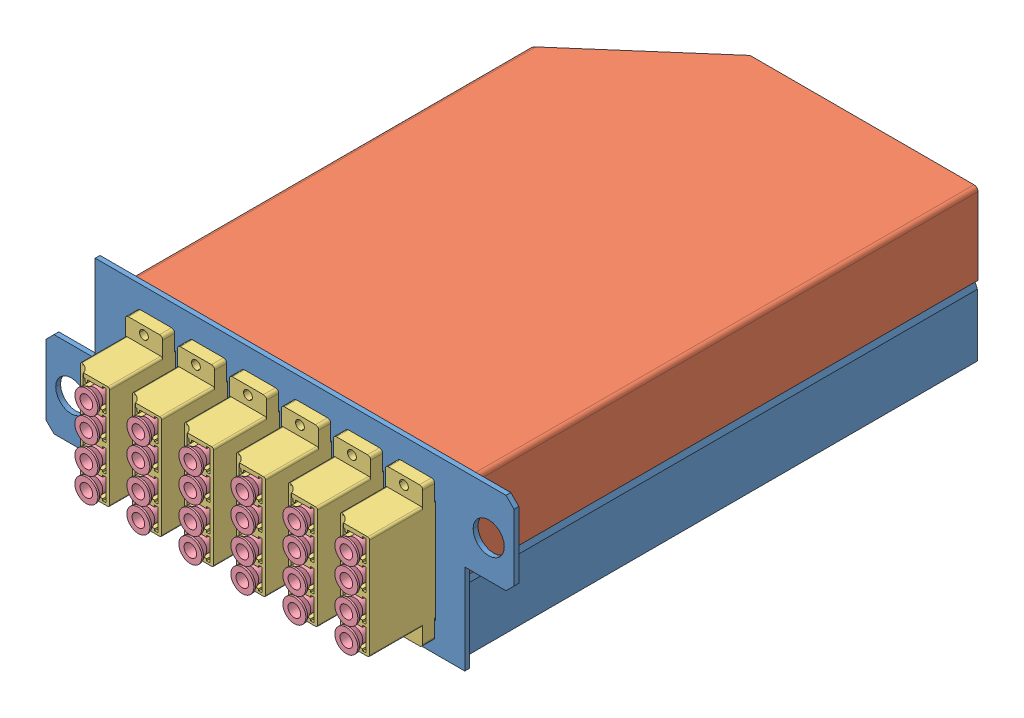
SolidWorks assembly Baugruppe5, configuration Standard. Lengths in mm.
Overall size (117 43.2 150.01).
62 component instances, 4 part files, 24 mates.
Components (placement in the parent):
- Cassette-1: Cassette [Standard] at (-81.5544 -7.2939 -1.2) size (117 43.2 131.2)
- Cassette Lid-1: Cassette Lid [Standard] at (-38.8731 -6.65 -32.039) size (86.6 20.2 130)
- LC-Adapter-1: LC-Adapter [Standard] at (-94.18 -5.525 16.25) x (0 1 0) z (0 0 1) size (34.9 10.05 34.47)
  - LC Adaptor-1: LC Adaptor [Standard] at (-28.4856 -9.35 -16.25) x (1 0 0) z (0 -1 0) size (34.9 25.75 9.35)
  - LC Adaptor Dust Cap-1: LC Adaptor Dust Cap [Standard] at (-27.05 -6.075 2.56) x (-0.837169 0.546944 0) z (-0.546944 -0.837169 0) size (5.75 16.66 5.75)
  - LC Adaptor Dust Cap-2: LC Adaptor Dust Cap [Standard] at (-20.85 -6.075 2.56) x (-0.837169 0.546944 0) z (-0.546944 -0.837169 0) size (5.75 16.66 5.75)
  - LC Adaptor Dust Cap-3: LC Adaptor Dust Cap [Standard] at (-14.05 -6.075 2.56) x (-0.837169 0.546944 0) z (-0.546944 -0.837169 0) size (5.75 16.66 5.75)
  - LC Adaptor Dust Cap-4: LC Adaptor Dust Cap [Standard] at (-7.85 -6.075 2.56) x (-0.837169 0.546944 0) z (-0.546944 -0.837169 0) size (5.75 16.66 5.75)
  - LC Adaptor Dust Cap-5: LC Adaptor Dust Cap [Standard] at (-27.05 -6.075 -31.91) x (0.972668 -0.232198 0) z (-0.232198 -0.972668 0) size (5.75 16.66 5.75)
  - LC Adaptor Dust Cap-6: LC Adaptor Dust Cap [Standard] at (-20.85 -6.075 -31.91) x (1 0 0) z (0 -1 0) size (5.75 16.66 5.75)
  - LC Adaptor Dust Cap-7: LC Adaptor Dust Cap [Standard] at (-14.05 -6.075 -31.91) x (0.97427 0.225385 0) z (0.225385 -0.97427 0) size (5.75 16.66 5.75)
  - LC Adaptor Dust Cap-8: LC Adaptor Dust Cap [Standard] at (-7.85 -6.075 -31.91) x (1 0 0) z (0 -1 0) size (5.75 16.66 5.75)
- LC-Adapter-2: LC-Adapter [Standard] at (-81.18 -5.525 16.25) x (0 1 0) z (0 0 1) size (34.9 10.05 34.47)
  - LC Adaptor-1: LC Adaptor [Standard] at (-28.4856 -9.35 -16.25) x (1 0 0) z (0 -1 0) size (34.9 25.75 9.35)
  - LC Adaptor Dust Cap-1: LC Adaptor Dust Cap [Standard] at (-27.05 -6.075 2.56) x (-0.837169 0.546944 0) z (-0.546944 -0.837169 0) size (5.75 16.66 5.75)
  - LC Adaptor Dust Cap-2: LC Adaptor Dust Cap [Standard] at (-20.85 -6.075 2.56) x (-0.837169 0.546944 0) z (-0.546944 -0.837169 0) size (5.75 16.66 5.75)
  - LC Adaptor Dust Cap-3: LC Adaptor Dust Cap [Standard] at (-14.05 -6.075 2.56) x (-0.837169 0.546944 0) z (-0.546944 -0.837169 0) size (5.75 16.66 5.75)
  - LC Adaptor Dust Cap-4: LC Adaptor Dust Cap [Standard] at (-7.85 -6.075 2.56) x (-0.837169 0.546944 0) z (-0.546944 -0.837169 0) size (5.75 16.66 5.75)
  - LC Adaptor Dust Cap-5: LC Adaptor Dust Cap [Standard] at (-27.05 -6.075 -31.91) x (0.972668 -0.232198 0) z (-0.232198 -0.972668 0) size (5.75 16.66 5.75)
  - LC Adaptor Dust Cap-6: LC Adaptor Dust Cap [Standard] at (-20.85 -6.075 -31.91) x (1 0 0) z (0 -1 0) size (5.75 16.66 5.75)
  - LC Adaptor Dust Cap-7: LC Adaptor Dust Cap [Standard] at (-14.05 -6.075 -31.91) x (0.97427 0.225385 0) z (0.225385 -0.97427 0) size (5.75 16.66 5.75)
  - LC Adaptor Dust Cap-8: LC Adaptor Dust Cap [Standard] at (-7.85 -6.075 -31.91) x (1 0 0) z (0 -1 0) size (5.75 16.66 5.75)
- LC-Adapter-3: LC-Adapter [Standard] at (-68.18 -5.525 16.25) x (0 1 0) z (0 0 1) size (34.9 10.05 34.47)
  - LC Adaptor-1: LC Adaptor [Standard] at (-28.4856 -9.35 -16.25) x (1 0 0) z (0 -1 0) size (34.9 25.75 9.35)
  - LC Adaptor Dust Cap-1: LC Adaptor Dust Cap [Standard] at (-27.05 -6.075 2.56) x (-0.837169 0.546944 0) z (-0.546944 -0.837169 0) size (5.75 16.66 5.75)
  - LC Adaptor Dust Cap-2: LC Adaptor Dust Cap [Standard] at (-20.85 -6.075 2.56) x (-0.837169 0.546944 0) z (-0.546944 -0.837169 0) size (5.75 16.66 5.75)
  - LC Adaptor Dust Cap-3: LC Adaptor Dust Cap [Standard] at (-14.05 -6.075 2.56) x (-0.837169 0.546944 0) z (-0.546944 -0.837169 0) size (5.75 16.66 5.75)
  - LC Adaptor Dust Cap-4: LC Adaptor Dust Cap [Standard] at (-7.85 -6.075 2.56) x (-0.837169 0.546944 0) z (-0.546944 -0.837169 0) size (5.75 16.66 5.75)
  - LC Adaptor Dust Cap-5: LC Adaptor Dust Cap [Standard] at (-27.05 -6.075 -31.91) x (0.972668 -0.232198 0) z (-0.232198 -0.972668 0) size (5.75 16.66 5.75)
  - LC Adaptor Dust Cap-6: LC Adaptor Dust Cap [Standard] at (-20.85 -6.075 -31.91) x (1 0 0) z (0 -1 0) size (5.75 16.66 5.75)
  - LC Adaptor Dust Cap-7: LC Adaptor Dust Cap [Standard] at (-14.05 -6.075 -31.91) x (0.97427 0.225385 0) z (0.225385 -0.97427 0) size (5.75 16.66 5.75)
  - LC Adaptor Dust Cap-8: LC Adaptor Dust Cap [Standard] at (-7.85 -6.075 -31.91) x (1 0 0) z (0 -1 0) size (5.75 16.66 5.75)
- LC-Adapter-4: LC-Adapter [Standard] at (-55.18 -5.525 16.25) x (0 1 0) z (0 0 1) size (34.9 10.05 34.47)
  - LC Adaptor-1: LC Adaptor [Standard] at (-28.4856 -9.35 -16.25) x (1 0 0) z (0 -1 0) size (34.9 25.75 9.35)
  - LC Adaptor Dust Cap-1: LC Adaptor Dust Cap [Standard] at (-27.05 -6.075 2.56) x (-0.837169 0.546944 0) z (-0.546944 -0.837169 0) size (5.75 16.66 5.75)
  - LC Adaptor Dust Cap-2: LC Adaptor Dust Cap [Standard] at (-20.85 -6.075 2.56) x (-0.837169 0.546944 0) z (-0.546944 -0.837169 0) size (5.75 16.66 5.75)
  - LC Adaptor Dust Cap-3: LC Adaptor Dust Cap [Standard] at (-14.05 -6.075 2.56) x (-0.837169 0.546944 0) z (-0.546944 -0.837169 0) size (5.75 16.66 5.75)
  - LC Adaptor Dust Cap-4: LC Adaptor Dust Cap [Standard] at (-7.85 -6.075 2.56) x (-0.837169 0.546944 0) z (-0.546944 -0.837169 0) size (5.75 16.66 5.75)
  - LC Adaptor Dust Cap-5: LC Adaptor Dust Cap [Standard] at (-27.05 -6.075 -31.91) x (0.972668 -0.232198 0) z (-0.232198 -0.972668 0) size (5.75 16.66 5.75)
  - LC Adaptor Dust Cap-6: LC Adaptor Dust Cap [Standard] at (-20.85 -6.075 -31.91) x (1 0 0) z (0 -1 0) size (5.75 16.66 5.75)
  - LC Adaptor Dust Cap-7: LC Adaptor Dust Cap [Standard] at (-14.05 -6.075 -31.91) x (0.97427 0.225385 0) z (0.225385 -0.97427 0) size (5.75 16.66 5.75)
  - LC Adaptor Dust Cap-8: LC Adaptor Dust Cap [Standard] at (-7.85 -6.075 -31.91) x (1 0 0) z (0 -1 0) size (5.75 16.66 5.75)
- LC-Adapter-5: LC-Adapter [Standard] at (-42.18 -5.525 16.25) x (0 1 0) z (0 0 1) size (34.9 10.05 34.47)
  - LC Adaptor-1: LC Adaptor [Standard] at (-28.4856 -9.35 -16.25) x (1 0 0) z (0 -1 0) size (34.9 25.75 9.35)
  - LC Adaptor Dust Cap-1: LC Adaptor Dust Cap [Standard] at (-27.05 -6.075 2.56) x (-0.837169 0.546944 0) z (-0.546944 -0.837169 0) size (5.75 16.66 5.75)
  - LC Adaptor Dust Cap-2: LC Adaptor Dust Cap [Standard] at (-20.85 -6.075 2.56) x (-0.837169 0.546944 0) z (-0.546944 -0.837169 0) size (5.75 16.66 5.75)
  - LC Adaptor Dust Cap-3: LC Adaptor Dust Cap [Standard] at (-14.05 -6.075 2.56) x (-0.837169 0.546944 0) z (-0.546944 -0.837169 0) size (5.75 16.66 5.75)
  - LC Adaptor Dust Cap-4: LC Adaptor Dust Cap [Standard] at (-7.85 -6.075 2.56) x (-0.837169 0.546944 0) z (-0.546944 -0.837169 0) size (5.75 16.66 5.75)
  - LC Adaptor Dust Cap-5: LC Adaptor Dust Cap [Standard] at (-27.05 -6.075 -31.91) x (0.972668 -0.232198 0) z (-0.232198 -0.972668 0) size (5.75 16.66 5.75)
  - LC Adaptor Dust Cap-6: LC Adaptor Dust Cap [Standard] at (-20.85 -6.075 -31.91) x (1 0 0) z (0 -1 0) size (5.75 16.66 5.75)
  - LC Adaptor Dust Cap-7: LC Adaptor Dust Cap [Standard] at (-14.05 -6.075 -31.91) x (0.97427 0.225385 0) z (0.225385 -0.97427 0) size (5.75 16.66 5.75)
  - LC Adaptor Dust Cap-8: LC Adaptor Dust Cap [Standard] at (-7.85 -6.075 -31.91) x (1 0 0) z (0 -1 0) size (5.75 16.66 5.75)
- LC-Adapter-6: LC-Adapter [Standard] at (-29.18 -5.525 16.25) x (0 1 0) z (0 0 1) size (34.9 10.05 34.47)
  - LC Adaptor-1: LC Adaptor [Standard] at (-28.4856 -9.35 -16.25) x (1 0 0) z (0 -1 0) size (34.9 25.75 9.35)
  - LC Adaptor Dust Cap-1: LC Adaptor Dust Cap [Standard] at (-27.05 -6.075 2.56) x (-0.837169 0.546944 0) z (-0.546944 -0.837169 0) size (5.75 16.66 5.75)
  - LC Adaptor Dust Cap-2: LC Adaptor Dust Cap [Standard] at (-20.85 -6.075 2.56) x (-0.837169 0.546944 0) z (-0.546944 -0.837169 0) size (5.75 16.66 5.75)
  - LC Adaptor Dust Cap-3: LC Adaptor Dust Cap [Standard] at (-14.05 -6.075 2.56) x (-0.837169 0.546944 0) z (-0.546944 -0.837169 0) size (5.75 16.66 5.75)
  - LC Adaptor Dust Cap-4: LC Adaptor Dust Cap [Standard] at (-7.85 -6.075 2.56) x (-0.837169 0.546944 0) z (-0.546944 -0.837169 0) size (5.75 16.66 5.75)
  - LC Adaptor Dust Cap-5: LC Adaptor Dust Cap [Standard] at (-27.05 -6.075 -31.91) x (0.972668 -0.232198 0) z (-0.232198 -0.972668 0) size (5.75 16.66 5.75)
  - LC Adaptor Dust Cap-6: LC Adaptor Dust Cap [Standard] at (-20.85 -6.075 -31.91) x (1 0 0) z (0 -1 0) size (5.75 16.66 5.75)
  - LC Adaptor Dust Cap-7: LC Adaptor Dust Cap [Standard] at (-14.05 -6.075 -31.91) x (0.97427 0.225385 0) z (0.225385 -0.97427 0) size (5.75 16.66 5.75)
  - LC Adaptor Dust Cap-8: LC Adaptor Dust Cap [Standard] at (-7.85 -6.075 -31.91) x (1 0 0) z (0 -1 0) size (5.75 16.66 5.75)
Mates (geometry in assembly coordinates):
- Deckungsgleich1: coincident: plane of Cassette-1 through (-81.5544 -7.2939 0) normal (0 0 1); plane of assembly
- Deckungsgleich2: coincident: plane of Cassette-1 through (-104.7 0 0) normal (0 1 0); plane of assembly
- Deckungsgleich3: coincident aligned: plane of Cassette-1 through (0 0 0) normal (1 0 0); plane of assembly
- Deckungsgleich4: coincident: plane of Cassette-1 through (-81.5544 -6.65 -1.2) normal (0 1 0); plane of Cassette Lid-1 through (-38.8731 -6.65 -32.039) normal (0 -1 0)
- Deckungsgleich5: coincident: plane of Cassette-1 through (-81.5544 -7.2939 -1.2) normal (0 0 -1); plane of Cassette Lid-1 through (-15.2 -5.45 -1.2) normal (0 0 1)
- Deckungsgleich6: coincident anti-aligned: plane of Cassette-1 through (-16.4 -25.3667 -131.2) normal (1 0 0); plane of Cassette Lid-1 through (-16.4 -25.65 -131.2) normal (-1 0 0)
- Konzentrisch1: concentric: cylinder of Cassette-1 through (-89.505 -7.525 -1.4) axis (0 0 1) radius 1.1; cylinder of LC-Adapter-1/LC Adaptor-1 through (-89.505 -7.525 -9.5) axis (0 0 1) radius 1.1
- Konzentrisch2: concentric: cylinder of Cassette-1 through (-76.505 -7.525 -1.4) axis (0 0 1) radius 1.1; cylinder of LC-Adapter-2/LC Adaptor-1 through (-76.505 -7.525 -9.5) axis (0 0 1) radius 1.1
- Konzentrisch3: concentric: cylinder of Cassette-1 through (-63.505 -7.525 -1.4) axis (0 0 1) radius 1.1; cylinder of LC-Adapter-3/LC Adaptor-1 through (-63.505 -7.525 -9.5) axis (0 0 1) radius 1.1
- Konzentrisch4: concentric: cylinder of Cassette-1 through (-50.505 -7.525 -1.4) axis (0 0 1) radius 1.1; cylinder of LC-Adapter-4/LC Adaptor-1 through (-50.505 -7.525 -9.5) axis (0 0 1) radius 1.1
- Konzentrisch5: concentric: cylinder of Cassette-1 through (-37.505 -7.525 -1.4) axis (0 0 1) radius 1.1; cylinder of LC-Adapter-5/LC Adaptor-1 through (-37.505 -7.525 -9.5) axis (0 0 1) radius 1.1
- Konzentrisch6: concentric: cylinder of Cassette-1 through (-24.505 -7.525 -1.4) axis (0 0 1) radius 1.1; cylinder of LC-Adapter-6/LC Adaptor-1 through (-24.505 -7.525 -9.5) axis (0 0 1) radius 1.1
- Konzentrisch7: concentric: cylinder of Cassette-1 through (-89.505 -38.425 -1.4) axis (0 0 1) radius 1.1; cylinder of LC-Adapter-1/LC Adaptor-1 through (-89.505 -38.425 -9.5) axis (0 0 1) radius 1.1
- Konzentrisch8: concentric: cylinder of Cassette-1 through (-76.505 -38.425 -1.4) axis (0 0 1) radius 1.1; cylinder of LC-Adapter-2/LC Adaptor-1 through (-76.505 -38.425 -9.5) axis (0 0 1) radius 1.1
- Konzentrisch9: concentric: cylinder of Cassette-1 through (-63.505 -38.425 -1.4) axis (0 0 1) radius 1.1; cylinder of LC-Adapter-3/LC Adaptor-1 through (-63.505 -38.425 -9.5) axis (0 0 1) radius 1.1
- Konzentrisch10: concentric: cylinder of Cassette-1 through (-50.505 -38.425 -1.4) axis (0 0 1) radius 1.1; cylinder of LC-Adapter-4/LC Adaptor-1 through (-50.505 -38.425 -9.5) axis (0 0 1) radius 1.1
- Konzentrisch11: concentric: cylinder of Cassette-1 through (-37.505 -38.425 -1.4) axis (0 0 1) radius 1.1; cylinder of LC-Adapter-5/LC Adaptor-1 through (-37.505 -38.425 -9.5) axis (0 0 1) radius 1.1
- Konzentrisch12: concentric: cylinder of Cassette-1 through (-24.505 -38.425 -1.4) axis (0 0 1) radius 1.1; cylinder of LC-Adapter-6/LC Adaptor-1 through (-24.505 -38.425 -9.5) axis (0 0 1) radius 1.1
- Deckungsgleich7: coincident anti-aligned: plane of Cassette-1 through (-81.5544 -7.2939 0) normal (0 0 1); plane of LC-Adapter-1/LC Adaptor-1 through (-94.18 -5.525 0) normal (0 0 -1)
- Deckungsgleich8: coincident anti-aligned: plane of Cassette-1 through (-81.5544 -7.2939 0) normal (0 0 1); plane of LC-Adapter-2/LC Adaptor-1 through (-81.18 -5.525 0) normal (0 0 -1)
- Deckungsgleich9: coincident anti-aligned: plane of Cassette-1 through (-81.5544 -7.2939 0) normal (0 0 1); plane of LC-Adapter-3/LC Adaptor-1 through (-68.18 -5.525 0) normal (0 0 -1)
- Deckungsgleich10: coincident anti-aligned: plane of Cassette-1 through (-81.5544 -7.2939 0) normal (0 0 1); plane of LC-Adapter-4/LC Adaptor-1 through (-55.18 -5.525 0) normal (0 0 -1)
- Deckungsgleich11: coincident anti-aligned: plane of Cassette-1 through (-81.5544 -7.2939 0) normal (0 0 1); plane of LC-Adapter-5/LC Adaptor-1 through (-42.18 -5.525 0) normal (0 0 -1)
- Deckungsgleich12: coincident anti-aligned: plane of Cassette-1 through (-81.5544 -7.2939 0) normal (0 0 1); plane of LC-Adapter-6/LC Adaptor-1 through (-29.18 -5.525 0) normal (0 0 -1)
